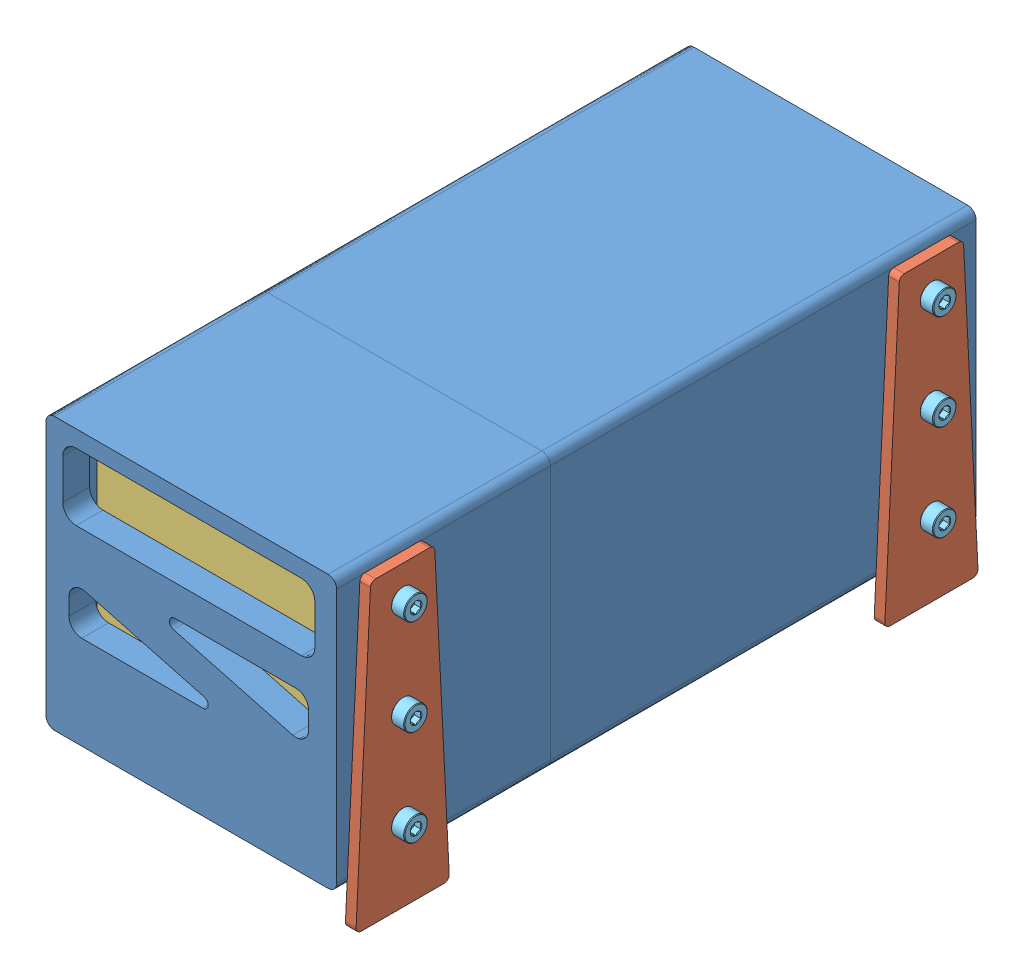
SolidWorks assembly EL-A0104-AA-LV Battery Assembly1, configuration Default. Lengths in mm.
Overall size (94.06 91.44 190.78).
16 component instances, 5 part files, 35 mates.
Components (placement in the parent):
- EL-50060-AA-LV Battery Enclosure1-2: EL-50060-AA-LV Battery Enclosure1 [Default] at (103.4038 95.6364 30.9853) size (86.72 81.15 190.78)
- EL-30061-AA-LV Battery Mounting Tab1-1: EL-30061-AA-LV Battery Mounting Tab1 [Default] at (147.5118 95.6364 125.9313) x (0 0 -1) z (0 -1 0) size (27.78 3.17 88.9)
- EL-30061-AA-LV Battery Mounting Tab1-2: EL-30061-AA-LV Battery Mounting Tab1 [Default] at (147.5118 95.6364 -31.8247) x (0 0 -1) z (0 -1 0) size (27.78 3.17 88.9)
- EL-00004-AA-Aegies-12 V 20 Ah Battery1-2: EL-00004-AA-Aegies-12 V 20 Ah Battery1 [Default] at (103.4038 55.5044 123.3053) x (0 0 1) z (0 1 0) size (167.64 76.2 76.2)
- FS-Heat Set Insert, M4x7-4.7 (94180A351)-1: FS-Heat Set Insert, M4x7-4.7 (94180A351) [94180A351] at (145.1618 124.2114 201.2513) x (0 -0.392341 -0.91982) z (1 0 0) size (6.35 6.35 4.7)
- FS-Heat Set Insert, M4x7-4.7 (94180A351)-2: FS-Heat Set Insert, M4x7-4.7 (94180A351) [94180A351] at (145.1618 95.6364 201.2513) x (0 -0.348719 -0.937227) z (1 0 0) size (6.35 6.35 4.7)
- FS-Heat Set Insert, M4x7-4.7 (94180A351)-3: FS-Heat Set Insert, M4x7-4.7 (94180A351) [94180A351] at (145.1618 67.0614 201.2513) x (0 -0.267668 -0.963511) z (1 0 0) size (6.35 6.35 4.7)
- FS-Heat Set Insert, M4x7-4.7 (94180A351)-4: FS-Heat Set Insert, M4x7-4.7 (94180A351) [94180A351] at (145.1618 67.0614 43.4953) x (0 -0.267487 -0.963562) z (1 0 0) size (6.35 6.35 4.7)
- FS-Heat Set Insert, M4x7-4.7 (94180A351)-5: FS-Heat Set Insert, M4x7-4.7 (94180A351) [94180A351] at (145.1618 95.6364 43.4953) x (0 -0.337845 -0.941202) z (1 0 0) size (6.35 6.35 4.7)
- FS-Heat Set Insert, M4x7-4.7 (94180A351)-6: FS-Heat Set Insert, M4x7-4.7 (94180A351) [94180A351] at (145.1618 124.2114 43.4953) x (0 -0.264568 -0.964367) z (1 0 0) size (6.35 6.35 4.7)
- BR-Black Oxide C12.9 SHCS, M4x0.7-8 (91290A140)1-2: BR-Black Oxide C12.9 SHCS, M4x0.7-8 (91290A140)1 [91290A140] at (148.6868 95.6364 43.4953) x (0 0 -1) z (1 0 0) size (7 7 12.17)
- BR-Black Oxide C12.9 SHCS, M4x0.7-8 (91290A140)1-3: BR-Black Oxide C12.9 SHCS, M4x0.7-8 (91290A140)1 [91290A140] at (148.6868 95.6364 201.2513) x (0 0 -1) z (1 0 0) size (7 7 12.17)
- BR-Black Oxide C12.9 SHCS, M4x0.7-8 (91290A140)1-4: BR-Black Oxide C12.9 SHCS, M4x0.7-8 (91290A140)1 [91290A140] at (148.6868 124.2114 201.2513) x (0 0 -1) z (1 0 0) size (7 7 12.17)
- BR-Black Oxide C12.9 SHCS, M4x0.7-8 (91290A140)1-5: BR-Black Oxide C12.9 SHCS, M4x0.7-8 (91290A140)1 [91290A140] at (148.6868 67.0614 43.4953) x (0 0 -1) z (1 0 0) size (7 7 12.17)
- BR-Black Oxide C12.9 SHCS, M4x0.7-8 (91290A140)1-6: BR-Black Oxide C12.9 SHCS, M4x0.7-8 (91290A140)1 [91290A140] at (148.6868 67.0614 201.2513) x (0 0 -1) z (1 0 0) size (7 7 12.17)
- BR-Black Oxide C12.9 SHCS, M4x0.7-8 (91290A140)1-7: BR-Black Oxide C12.9 SHCS, M4x0.7-8 (91290A140)1 [91290A140] at (148.6868 124.2114 43.4953) x (0 0 -1) z (1 0 0) size (7 7 12.17)
Mates (geometry in assembly coordinates):
- Concentric1: concentric aligned: cylinder of EL-50060-AA-LV Battery Enclosure-2 through (128.0118 124.2114 201.2513) axis (1 0 0) radius 3.025; circle of LV-Mounting-Tab-1
- Concentric2: concentric aligned: cylinder of EL-50060-AA-LV Battery Enclosure-2 through (128.0118 95.6364 201.2513) axis (1 0 0) radius 3.025; cylinder of EL-30061-AA-LV Battery Mounting Tab-1 through (150.6868 95.6364 201.2513) axis (1 0 0) radius 2.25
- Concentric3: concentric aligned: cylinder of EL-50060-AA-LV Battery Enclosure-2 through (128.0118 67.0614 201.2513) axis (1 0 0) radius 3.025; cylinder of EL-30061-AA-LV Battery Mounting Tab-1 through (150.6868 67.0614 201.2513) axis (1 0 0) radius 2.25
- Coincident1: coincident anti-aligned: plane of EL-50060-AA-LV Battery Enclosure-2 through (147.5118 95.6364 30.9853) normal (1 0 0); plane of EL-30061-AA-LV Battery Mounting Tab-1 through (147.5118 132.1474 209.3266) normal (-1 0 0)
- Concentric4: concentric aligned: cylinder of EL-50060-AA-LV Battery Enclosure-2 through (128.0118 124.2114 43.4953) axis (1 0 0) radius 3.025; cylinder of LV-Mounting-Tab-2 through (150.6868 124.2114 43.4953) axis (1 0 0) radius 2.25
- Concentric5: concentric aligned: cylinder of EL-50060-AA-LV Battery Enclosure-2 through (128.0118 95.6364 43.4953) axis (1 0 0) radius 3.025; cylinder of LV-Mounting-Tab-2 through (150.6868 95.6364 43.4953) axis (1 0 0) radius 2.25
- Concentric6: concentric aligned: cylinder of EL-50060-AA-LV Battery Enclosure-2 through (128.0118 67.0614 43.4953) axis (1 0 0) radius 3.025; cylinder of LV-Mounting-Tab-2 through (150.6868 67.0614 43.4953) axis (1 0 0) radius 2.25
- Coincident2: coincident anti-aligned: plane of EL-50060-AA-LV Battery Enclosure-2 through (147.5118 95.6364 30.9853) normal (1 0 0); plane of LV-Mounting-Tab-2 through (147.5118 132.1474 51.5706) normal (-1 0 0)
- Concentric7: concentric aligned: cylinder of EL-50060-AA-LV Battery Enclosure-2 through (128.0118 124.2114 201.2513) axis (1 0 0) radius 3.025; circle of FS-Heat Set Insert, M4x7-4.7 (94180A351)-1
- Coincident3: coincident aligned: plane of EL-50060-AA-LV Battery Enclosure-2 through (147.5118 95.6364 30.9853) normal (1 0 0); circle of FS-Heat Set Insert, M4x7-4.7 (94180A351)-1
- Concentric8: concentric aligned: cylinder of EL-50060-AA-LV Battery Enclosure-2 through (128.0118 95.6364 201.2513) axis (1 0 0) radius 3.025; cylinder of FS-Heat Set Insert, M4x7-4.7 (94180A351)-2 through (147.5118 95.6364 201.2513) axis (1 0 0) radius 3.175
- Coincident4: coincident aligned: plane of EL-50060-AA-LV Battery Enclosure-2 through (147.5118 95.6364 30.9853) normal (1 0 0); circle of FS-Heat Set Insert, M4x7-4.7 (94180A351)-2
- Concentric9: concentric aligned: cylinder of EL-50060-AA-LV Battery Enclosure-2 through (128.0118 67.0614 201.2513) axis (1 0 0) radius 3.025; cylinder of FS-Heat Set Insert, M4x7-4.7 (94180A351)-3 through (147.5118 67.0614 201.2513) axis (1 0 0) radius 3.175
- Coincident5: coincident aligned: plane of EL-50060-AA-LV Battery Enclosure-2 through (147.5118 95.6364 30.9853) normal (1 0 0); circle of FS-Heat Set Insert, M4x7-4.7 (94180A351)-3
- Concentric10: concentric aligned: cylinder of EL-50060-AA-LV Battery Enclosure-2 through (128.0118 67.0614 43.4953) axis (1 0 0) radius 3.025; cylinder of FS-Heat Set Insert, M4x7-4.7 (94180A351)-4 through (147.5118 67.0614 43.4953) axis (1 0 0) radius 3.175
- Coincident6: coincident aligned: plane of EL-50060-AA-LV Battery Enclosure-2 through (147.5118 95.6364 30.9853) normal (1 0 0); circle of FS-Heat Set Insert, M4x7-4.7 (94180A351)-4
- Concentric11: concentric aligned: cylinder of EL-50060-AA-LV Battery Enclosure-2 through (128.0118 95.6364 43.4953) axis (1 0 0) radius 3.025; cylinder of FS-Heat Set Insert, M4x7-4.7 (94180A351)-5 through (147.5118 95.6364 43.4953) axis (1 0 0) radius 3.175
- Coincident7: coincident aligned: plane of EL-50060-AA-LV Battery Enclosure-2 through (147.5118 95.6364 30.9853) normal (1 0 0); circle of FS-Heat Set Insert, M4x7-4.7 (94180A351)-5
- Concentric12: concentric aligned: cylinder of EL-50060-AA-LV Battery Enclosure-2 through (128.0118 124.2114 43.4953) axis (1 0 0) radius 3.025; cylinder of FS-Heat Set Insert, M4x7-4.7 (94180A351)-6 through (147.5118 124.2114 43.4953) axis (1 0 0) radius 3.175
- Coincident8: coincident aligned: plane of EL-50060-AA-LV Battery Enclosure-2 through (147.5118 95.6364 30.9853) normal (1 0 0); circle of FS-Heat Set Insert, M4x7-4.7 (94180A351)-6
- Distance1: distance = 0.508 mm anti-aligned: plane of EL-00004-AA-Aegies-12 V 20 Ah Battery-2 through (103.4038 131.7044 123.3053) normal (0 1 0); plane of EL-50060-AA-LV Battery Enclosure-2 through (60.7958 132.2124 213.7613) normal (0 -1 0)
- Distance2: distance = 0.508 mm anti-aligned: plane of EL-00004-AA-Aegies-12 V 20 Ah Battery-2 through (141.5038 131.7044 39.4853) normal (1 0 0); plane of EL-50060-AA-LV Battery Enclosure-2 through (142.0118 136.2124 213.7613) normal (-1 0 0)
- Coincident12: coincident anti-aligned: plane of EL-50060-AA-LV Battery Enclosure-2 through (103.4038 95.6364 39.4853) normal (0 0 1); plane of EL-00004-AA-Aegies-12 V 20 Ah Battery-2 through (141.5038 131.7044 39.4853) normal (0 0 -1)
- Concentric13: concentric anti-aligned: cylinder of EL-30061-AA-LV Battery Mounting Tab-1 through (150.6868 124.2114 201.2513) axis (1 0 0) radius 2.25; cylinder of BR-Black Oxide C12.9 SHCS, M4x0.7-8 (91290A140)-4 through (142.6868 124.2114 201.2513) axis (-1 0 0) radius 2
- Coincident13: coincident anti-aligned: plane of EL-30061-AA-LV Battery Mounting Tab-1 through (150.6868 132.1474 209.3266) normal (1 0 0); plane of BR-Black Oxide C12.9 SHCS, M4x0.7-8 (91290A140)-4 through (150.6868 127.5114 201.2513) normal (-1 0 0)
- Concentric14: concentric anti-aligned: cylinder of EL-30061-AA-LV Battery Mounting Tab-1 through (150.6868 95.6364 201.2513) axis (1 0 0) radius 2.25; cylinder of BR-Black Oxide C12.9 SHCS, M4x0.7-8 (91290A140)-3 through (142.6868 95.6364 201.2513) axis (-1 0 0) radius 2
- Coincident14: coincident anti-aligned: plane of EL-30061-AA-LV Battery Mounting Tab-1 through (150.6868 132.1474 209.3266) normal (1 0 0); plane of BR-Black Oxide C12.9 SHCS, M4x0.7-8 (91290A140)-3 through (150.6868 98.9364 201.2513) normal (-1 0 0)
- Concentric15: concentric anti-aligned: cylinder of EL-30061-AA-LV Battery Mounting Tab-1 through (150.6868 67.0614 201.2513) axis (1 0 0) radius 2.25; cylinder of BR-Black Oxide C12.9 SHCS, M4x0.7-8 (91290A140)-6 through (142.6868 67.0614 201.2513) axis (-1 0 0) radius 2
- Coincident15: coincident anti-aligned: plane of EL-30061-AA-LV Battery Mounting Tab-1 through (150.6868 132.1474 209.3266) normal (1 0 0); plane of BR-Black Oxide C12.9 SHCS, M4x0.7-8 (91290A140)-6 through (150.6868 70.3614 201.2513) normal (-1 0 0)
- Concentric16: concentric anti-aligned: cylinder of LV-Mounting-Tab-2 through (150.6868 124.2114 43.4953) axis (1 0 0) radius 2.25; cylinder of BR-Black Oxide C12.9 SHCS, M4x0.7-8 (91290A140)-7 through (142.6868 124.2114 43.4953) axis (-1 0 0) radius 2
- Coincident16: coincident anti-aligned: plane of LV-Mounting-Tab-2 through (150.6868 132.1474 51.5706) normal (1 0 0); plane of BR-Black Oxide C12.9 SHCS, M4x0.7-8 (91290A140)-7 through (150.6868 127.5114 43.4953) normal (-1 0 0)
- Concentric17: concentric anti-aligned: cylinder of LV-Mounting-Tab-2 through (150.6868 95.6364 43.4953) axis (1 0 0) radius 2.25; cylinder of BR-Black Oxide C12.9 SHCS, M4x0.7-8 (91290A140)-2 through (142.6868 95.6364 43.4953) axis (-1 0 0) radius 2
- Coincident17: coincident anti-aligned: plane of LV-Mounting-Tab-2 through (150.6868 132.1474 51.5706) normal (1 0 0); plane of BR-Black Oxide C12.9 SHCS, M4x0.7-8 (91290A140)-2 through (150.6868 98.9364 43.4953) normal (-1 0 0)
- Concentric18: concentric anti-aligned: cylinder of LV-Mounting-Tab-2 through (150.6868 67.0614 43.4953) axis (1 0 0) radius 2.25; cylinder of BR-Black Oxide C12.9 SHCS, M4x0.7-8 (91290A140)-5 through (142.6868 67.0614 43.4953) axis (-1 0 0) radius 2
- Coincident18: coincident anti-aligned: plane of LV-Mounting-Tab-2 through (150.6868 132.1474 51.5706) normal (1 0 0); plane of BR-Black Oxide C12.9 SHCS, M4x0.7-8 (91290A140)-5 through (150.6868 70.3614 43.4953) normal (-1 0 0)
